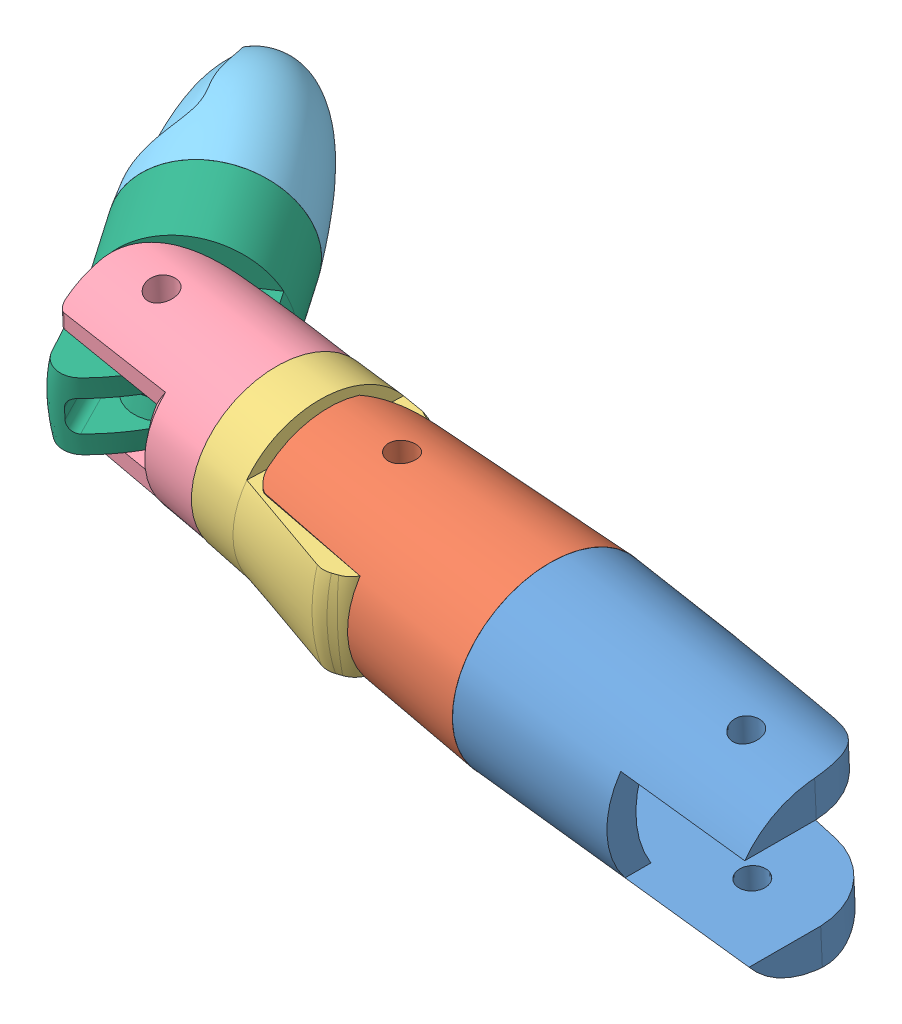
SolidWorks assembly majeur, configuration Varsayılan. Lengths in mm.
Overall size (93.27 24.14 46.87).
6 component instances, 6 part files, 15 mates.
Components (placement in the parent):
- majeur3-4-1: majeur3-4 [Varsayılan] at (8.008 -20.3817 -24.6492) x (-0.04716 -0.994751 -0.090807) z (-0.088288 -0.086402 0.992341) size (17.93 28.49 17.93)
- majeur3-3-1: majeur3-3 [Varsayılan] at (8.008 -20.3817 -24.6492) x (0.994978 -0.054816 0.08375) z (-0.088288 -0.086402 0.992341) size (23.21 17.94 17.94)
- majeur3-5-1: majeur3-5 [Varsayılan] at (-20.6209 -18.7646 -27.4956) x (0.991343 -0.057762 0.117906) z (-0.04716 -0.994751 -0.090807) size (18.43 17.42 16.26)
- majeur3-6-1: majeur3-6 [Varsayılan] at (-37.3548 -17.7896 -29.4858) x (0.991343 -0.057762 0.117906) z (0.122532 0.084461 -0.988864) size (16.88 15.98 15.75)
- Paramak ucu majeur3-1: Paramak ucu majeur3 [Varsayılan] at (-39.2647 -16.7815 -39.537) x (0.04716 0.994751 0.090807) z (-0.838175 -0.010042 0.545308) size (14.78 18.22 14.78)
- majeur3-2-1: majeur3-2 [Varsayılan] at (-39.2647 -16.7815 -39.537) x (-0.838175 -0.010042 0.545308) z (0.543358 -0.101829 0.833302) size (15.56 14.88 19.06)
Mates (geometry in assembly coordinates):
- Coincident1: coincident anti-aligned: plane of majeur3-2-1 through (-37.1123 -16.7882 -40.5814) normal (-0.389556 0.102026 -0.915334); plane of Paramak ucu majeur3-1 through (-32.3807 -16.8283 -42.5995) normal (0.389556 -0.102026 0.915334)
- Coincident2: coincident aligned: circle of majeur3-2-1; circle of Paramak ucu majeur3-1
- Coincident3: coincident anti-aligned: plane of majeur3-5-1 through (-20.6209 -18.7646 -27.4956) normal (-0.991343 0.057762 -0.117906); plane of majeur3-6-1 through (-22.7472 -43.8329 -21.8986) normal (0.991343 -0.057762 0.117906)
- Concentric1: concentric aligned: cone of majeur3-5-1 through (-20.6209 -18.7646 -27.4956) axis (-0.991343 0.057762 -0.117906); cone of majeur3-6-1 through (-18.5291 -18.8865 -27.2468) axis (-0.991343 0.057762 -0.117906)
- Coincident4: coincident anti-aligned: plane of majeur3-3-1 through (8.008 -20.3817 -24.6492) normal (0.994978 -0.054816 0.08375); plane of majeur3-4-1 through (8.008 -20.3817 -24.6492) normal (-0.994978 0.054816 -0.08375)
- Concentric2: concentric anti-aligned: cone of majeur3-3-1 through (-15.0854 -19.1094 -26.5931) axis (-0.994978 0.054816 -0.08375); cone of majeur3-4-1 through (8.008 -20.3817 -24.6492) axis (0.994978 -0.054816 0.08375)
- Coincident5: coincident anti-aligned: plane of majeur3-3-1 through (6.8651 -25.7535 -14.5872) normal (0.04716 0.994751 0.090807); plane of majeur3-5-1 through (-10.2247 -23.9586 -25.3731) normal (-0.04716 -0.994751 -0.090807)
- Concentric3: concentric aligned: cylinder of majeur3-3-1 through (-7.5083 -8.9567 -25.5665) axis (-0.04716 -0.994751 -0.090807) radius 1.3188; cylinder of majeur3-5-1 through (-7.6224 -11.363 -25.7862) axis (-0.04716 -0.994751 -0.090807) radius 1.3188
- Coincident8: coincident anti-aligned: plane of majeur3-6-1 through (-37.5165 -21.2003 -29.7972) normal (0.04716 0.994751 0.090807); plane of majeur3-2-1 through (-43.9208 -20.3446 -35.8455) normal (-0.04716 -0.994751 -0.090807)
- Concentric6: concentric aligned: cylinder of majeur3-6-1 through (-31.8815 -10.3124 -27.1021) axis (-0.04716 -0.994751 -0.090807) radius 1.3188; cylinder of majeur3-2-1 through (-31.9039 -10.7847 -27.1452) axis (-0.04716 -0.994751 -0.090807) radius 1.3188
- Coincident9: coincident aligned: plane of majeur3-4-1 through (8.008 -20.3817 -24.6492) normal (-0.088288 -0.086402 0.992341); plane of majeur3-3-1 through (8.008 -20.3817 -24.6492) normal (-0.088288 -0.086402 0.992341)
- Coincident10: coincident anti-aligned: plane of majeur3-5-1; plane of majeur3-6-1 through (-37.3548 -17.7896 -29.4858) normal (0.122532 0.084461 -0.988864)
- Coincident11: coincident aligned: plane of Paramak ucu majeur3-1 through (-37.1123 -16.7882 -40.5814) normal (-0.919795 0.007793 0.392323); plane of majeur3-2-1
- LimitAngle1: limit planar angle = 3.107116 rad anti-aligned: plane of majeur3-3-1 through (8.008 -20.3817 -24.6492) normal (-0.088288 -0.086402 0.992341); plane of majeur3-5-1
- LimitAngle2: limit planar angle = 0.872665 rad anti-aligned: plane of majeur3-2-1; plane of majeur3-6-1 through (-37.3548 -17.7896 -29.4858) normal (0.122532 0.084461 -0.988864)
